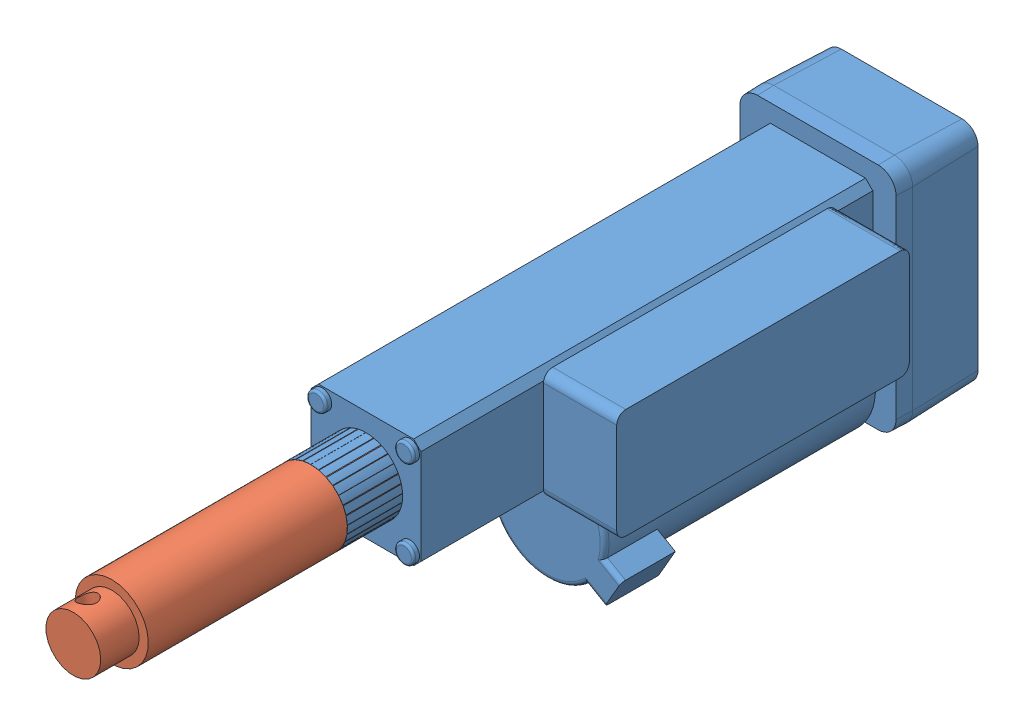
SolidWorks assembly actuator, configuration Default. Lengths in mm.
Overall size (71.75 88.27 336.55).
2 component instances, 2 part files, 2 mates.
Components (placement in the parent):
- 6530K111-1: 6530K111 [6530K111] at (-70.9129 29.2134 -102.4944) size (71.75 88.27 336.55)
- Part1^actuator-1: Part1^actuator [Default] at (-70.9129 29.2134 -135.0064) x (-0.219296 0.975658 0) z (0 0 1) size (25.4 25.4 114.94) (virtual)
Mates (geometry in assembly coordinates):
- Concentric1: concentric aligned: circle of 6530K111-1; circle of Part1^actuator-1
- LimitDistance1: limit distance = 101.6 mm aligned: plane of Part1^actuator-1 through (-70.9129 29.2134 161.5386) normal (0 0 1); plane of 6530K111-1 through (-70.9129 29.2134 59.9386) normal (0 0 1)
